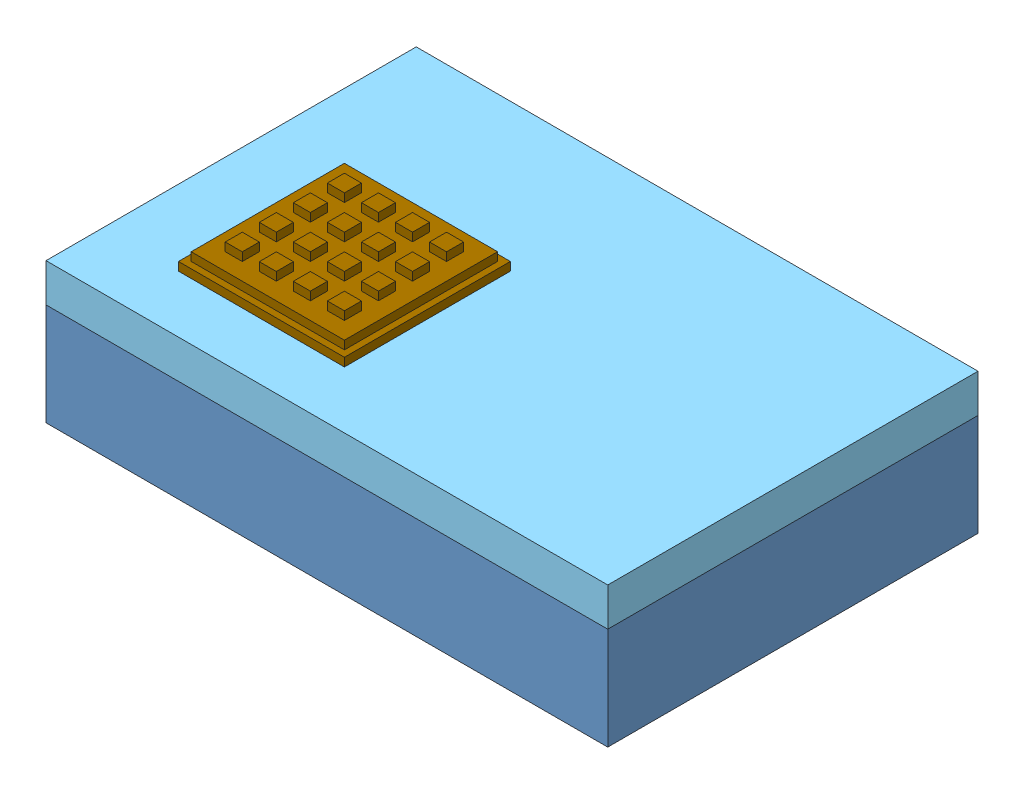
SolidWorks assembly PICase_Assembly_v6, configuration Default. Lengths in mm.
Overall size (220 64.9 145).
10 component instances, 9 part files, 31 mates.
Components (placement in the parent):
- PICase220x145x55_v1-1: PICase220x145x55_v1 [Default] at (-152.1826 -9.2207 87.4359) size (220 40 145)
- 12Vto5VMicroUsb_v1-1: 12Vto5VMicroUsb_v1 [Default] at (14.0667 11.0853 84.4359) x (1 0 0) z (0 1 0) size (63 14 42)
- RaspberryPi3B_v1-1: RaspberryPi3B_v1 [Default] at (-29.1826 -5.6074 11.5724) size (94 31 65.5)
- ProtoBoard_v1-1: ProtoBoard_v1 [Default] at (-38.7137 11.421 -33.3718) x (-1 0 0) z (0 0 -1) size (80.96 1.59 50.8)
- ProtoBoard_v1-2: ProtoBoard_v1 [Default] at (-84.4068 17.9548 33.5257) x (0 0 -1) z (1 0 0) size (80.96 1.59 50.8)
- PICase_LID_220x145x55_v1-1: PICase_LID_220x145x55_v1 [Default] at (-152.1826 45.7793 -57.5641) x (1 0 0) z (0 0 -1) size (220 15 145)
- PowerSupply_v2-1: PowerSupply_v2 [Default] at (-149.1826 -6.2207 84.4359) size (138.11 32.54 53.98)
- 7seg_v1-1: 7seg_v1 [Default] at (-125.1662 33.2543 -18.3108) size (66 9.53 27)
- LCD_126x64_v1-1: LCD_126x64_v1 [Default] at (-41.1894 32.4605 73.3158) size (93.66 10.32 69.85)
- keyPad_4x4_v1-1: keyPad_4x4_v1 [Default] at (-122.6764 45.7793 65.0768) size (65 9.9 65)
Mates (geometry in assembly coordinates):
- Parallel1: parallel anti-aligned: plane of PICase220x145x55_v1-1 through (-152.1826 -6.2207 87.4359) normal (0 1 0); plane of RaspberryPi3B_v1-1 through (-29.1826 -5.6074 11.5724) normal (0 -1 0)
- Parallel2: parallel anti-aligned: plane of PICase220x145x55_v1-1 through (-152.1826 -6.2207 87.4359) normal (0 1 0); plane of ProtoBoard_v1-1 through (-38.7137 11.421 -33.3718) normal (0 -1 0)
- Parallel4: parallel anti-aligned: plane of PICase220x145x55_v1-1 through (-152.1826 -9.2207 87.4359) normal (0 -1 0); plane of PICase_LID_220x145x55_v1-1 through (-152.1826 45.7793 -57.5641) normal (0 1 0)
- Coincident6: coincident aligned: plane of PICase220x145x55_v1-1 through (-152.1826 -6.2207 87.4359) normal (-1 0 0); plane of PICase_LID_220x145x55_v1-1 through (-152.1826 42.7793 -57.5641) normal (-1 0 0)
- Coincident9: coincident aligned: plane of PICase220x145x55_v1-1 through (-152.1826 -6.2207 87.4359) normal (0 0 1); plane of PICase_LID_220x145x55_v1-1 through (-152.1826 42.7793 87.4359) normal (0 0 1)
- LimitDistance1: limit distance = 0 mm anti-aligned: plane of PICase220x145x55_v1-1 through (-152.1826 30.7793 87.4359) normal (0 1 0); plane of PICase_LID_220x145x55_v1-1 through (-152.1826 30.7793 -57.5641) normal (0 -1 0)
- LimitDistance2: limit distance = 0.6133 mm anti-aligned: plane of RaspberryPi3B_v1-1 through (-29.1826 -5.6074 11.5724) normal (0 -1 0); plane of PICase220x145x55_v1-1 through (-152.1826 -6.2207 87.4359) normal (0 1 0)
- LimitDistance4: limit distance = 120 mm anti-aligned: plane of RaspberryPi3B_v1-1 through (-29.1826 25.3926 11.5724) normal (-1 0 0); plane of PICase220x145x55_v1-1 through (-149.1826 334.2655 -35.8641) normal (1 0 0)
- LimitDistance6: limit distance = 72.8635 mm anti-aligned: plane of PICase220x145x55_v1-1 through (-140.6826 334.2655 84.4359) normal (0 0 -1); plane of RaspberryPi3B_v1-1 through (-29.1826 25.3926 11.5724) normal (0 0 1)
- LimitDistance5: limit distance = 0.6133 mm anti-aligned: plane of RaspberryPi3B_v1-1 through (-29.1826 -5.6074 11.5724) normal (0 -1 0); plane of PICase220x145x55_v1-1 through (-152.1826 -6.2207 87.4359) normal (0 1 0)
- Parallel5: parallel anti-aligned: plane of PICase220x145x55_v1-1 through (-152.1826 -6.2207 87.4359) normal (0 1 0); plane of PowerSupply_v2-1 through (-149.1826 -6.2207 84.4359) normal (0 -1 0)
- Parallel6: parallel aligned: plane of PICase220x145x55_v1-1 through (-152.1826 -6.2207 87.4359) normal (0 0 1); plane of PowerSupply_v2-1 through (-149.1826 26.323 84.4359) normal (0 0 1)
- Parallel7: parallel aligned: plane of PICase220x145x55_v1-1 through (-152.1826 -6.2207 87.4359) normal (-1 0 0); plane of PowerSupply_v2-1 through (-149.1826 26.323 84.4359) normal (-1 0 0)
- LimitDistance7: limit distance = 0 mm anti-aligned: plane of PowerSupply_v2-1 through (-149.1826 26.323 84.4359) normal (-1 0 0); plane of PICase220x145x55_v1-1 through (-149.1826 334.2655 -35.8641) normal (1 0 0)
- LimitDistance8: limit distance = 0 mm anti-aligned: plane of PowerSupply_v2-1 through (-149.1826 26.323 84.4359) normal (0 0 1); plane of PICase220x145x55_v1-1 through (-140.6826 334.2655 84.4359) normal (0 0 -1)
- LimitDistance9: limit distance = 0 mm anti-aligned: plane of PowerSupply_v2-1 through (-149.1826 -6.2207 84.4359) normal (0 -1 0); plane of PICase220x145x55_v1-1 through (-152.1826 -6.2207 87.4359) normal (0 1 0)
- LimitDistance10: limit distance = 17.6417 mm anti-aligned: plane of ProtoBoard_v1-1 through (-38.7137 11.421 -33.3718) normal (0 -1 0); plane of PICase220x145x55_v1-1 through (-152.1826 -6.2207 87.4359) normal (0 1 0)
- LimitDistance11: limit distance = 29.5063 mm anti-aligned: plane of PICase220x145x55_v1-1 through (-149.1826 334.2655 -35.8641) normal (1 0 0); plane of ProtoBoard_v1-1 through (-119.6762 13.0085 -33.3718) normal (-1 0 0)
- LimitDistance12: limit distance = 67.0077 mm anti-aligned: plane of PICase220x145x55_v1-1 through (-140.6826 334.2655 84.4359) normal (0 0 -1); plane of ProtoBoard_v1-1 through (-38.7137 13.0085 17.4282) normal (0 0 1)
- LimitDistance13: limit distance = 50.9101 mm anti-aligned: plane of PICase220x145x55_v1-1 through (-140.6826 334.2655 84.4359) normal (0 0 -1); plane of ProtoBoard_v1-2 through (-84.4068 19.5423 33.5257) normal (0 0 1)
- LimitDistance14: limit distance = 24.1755 mm anti-aligned: plane of PICase220x145x55_v1-1 through (-152.1826 -6.2207 87.4359) normal (0 1 0); plane of ProtoBoard_v1-2 through (-84.4068 17.9548 33.5257) normal (0 -1 0)
- LimitDistance15: limit distance = 13.9757 mm anti-aligned: plane of PICase220x145x55_v1-1 through (-149.1826 334.2655 -35.8641) normal (1 0 0); plane of ProtoBoard_v1-2 through (-135.2068 19.5423 33.5257) normal (-1 0 0)
- Coincident11: coincident anti-aligned: plane of PICase220x145x55_v1-1 through (-140.6826 334.2655 84.4359) normal (0 0 -1); plane of 12Vto5VMicroUsb_v1-1 through (14.0667 11.0853 84.4359) normal (0 0 1)
- Parallel8: parallel aligned: plane of PICase220x145x55_v1-1 through (-152.1826 -9.2207 87.4359) normal (0 -1 0); plane of 12Vto5VMicroUsb_v1-1 through (-8.9333 -4.9147 70.4359) normal (0 -1 0)
- LimitDistance16: limit distance = 1.306 mm anti-aligned: plane of PICase220x145x55_v1-1 through (-152.1826 -6.2207 87.4359) normal (0 1 0); plane of 12Vto5VMicroUsb_v1-1 through (-8.9333 -4.9147 70.4359) normal (0 -1 0)
- Coincident12: coincident anti-aligned: plane of PICase_LID_220x145x55_v1-1 through (-152.1826 42.7793 -57.5641) normal (0 -1 0); plane of 7seg_v1-1 through (-125.1662 42.7793 -18.3108) normal (0 1 0)
- Parallel9: parallel aligned: plane of PICase220x145x55_v1-1 through (-152.1826 -6.2207 -57.5641) normal (0 0 -1); plane of 7seg_v1-1 through (-119.4912 42.7793 -41.3358) normal (0 0 -1)
- Coincident14: coincident anti-aligned: plane of PICase_LID_220x145x55_v1-1 through (-152.1826 42.7793 -57.5641) normal (0 -1 0); plane of LCD_126x64_v1-1 through (-41.1894 42.7793 73.3158) normal (0 1 0)
- Parallel10: parallel aligned: plane of PICase220x145x55_v1-1 through (-152.1826 -6.2207 87.4359) normal (0 0 1); plane of LCD_126x64_v1-1 through (-41.1894 34.048 73.3158) normal (0 0 1)
- Coincident15: coincident anti-aligned: plane of PICase_LID_220x145x55_v1-1 through (-152.1826 45.7793 -57.5641) normal (0 1 0); plane of keyPad_4x4_v1-1 through (-122.6764 45.7793 65.0768) normal (0 -1 0)
- Parallel11: parallel aligned: plane of PICase220x145x55_v1-1 through (-152.1826 -6.2207 87.4359) normal (0 0 1); plane of keyPad_4x4_v1-1 through (-122.6764 49.0793 65.0768) normal (0 0 1)
